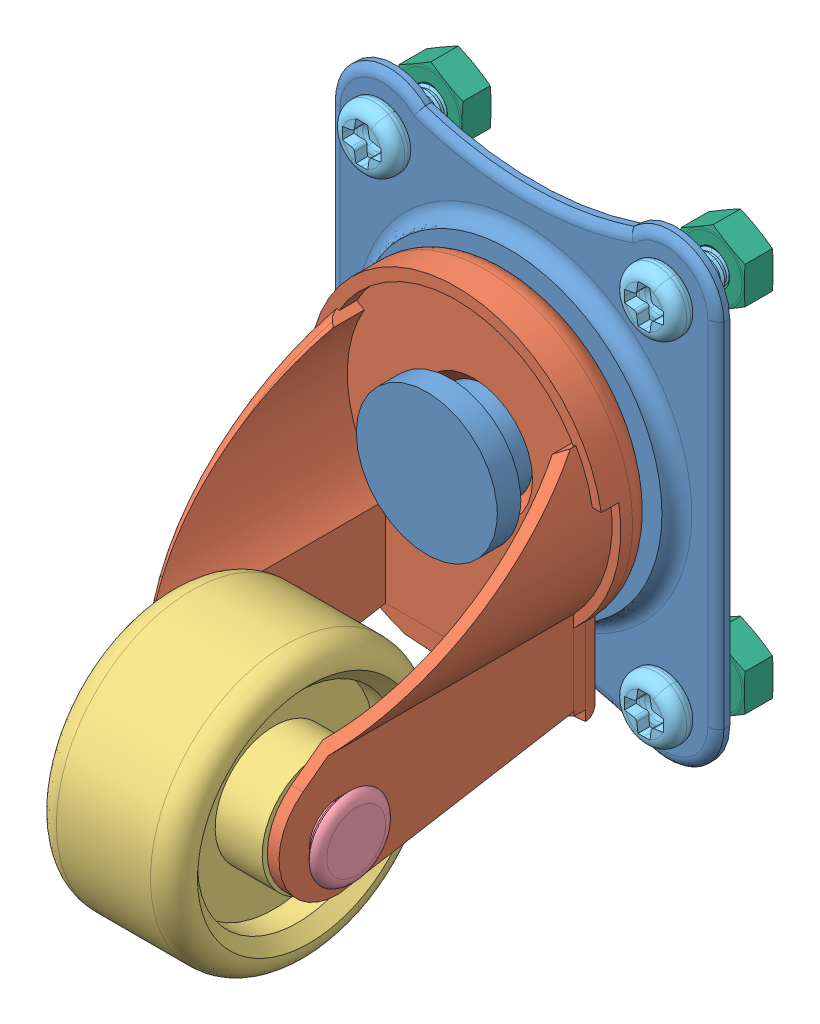
SolidWorks assembly CA, configuration Predeterminado. Lengths in mm.
Overall size (33 45.94 43.2).
13 component instances, 6 part files, 16 mates.
Components (placement in the parent):
- Caster Wheel-1: Caster Wheel [Default] at (57.6387 -78.841 57.7572) x (0 1 0) z (-1 0 0) size (45.94 37.59 33)
  - caster holder-1: caster holder [Default] at (-24.0751 44.7184 29.5137) x (1 0 0) z (0 0 -1) size (39 9.27 33)
  - holder-1: holder [Default] at (-1.5751 42.9484 46.0137) x (0 0 1) z (1 0 0) size (25 28.07 31.31)
  - caster wheel-1: caster wheel [Default] at (-15.6961 19.9484 46.0137) x (0.997275 0.073773 0) z (0 0 1) size (23 23 14)
  - Part4-1: Part4 [Default] at (-15.6961 19.9484 55.0137) x (-0.978448 0.206495 0) z (0 0 -1) size (7 7 20)
- M3x6 Philips Screw-1: M3x6 Philips Screw [Predeterminado] at (23.625 -65.4161 13.5389) size (5.3 5.3 7.81)
- M3x6 Philips Screw-2: M3x6 Philips Screw [Predeterminado] at (-0.375 -65.4161 13.5389) size (5.3 5.3 7.81)
- M3x6 Philips Screw-3: M3x6 Philips Screw [Predeterminado] at (-0.375 -95.4161 13.5389) size (5.3 5.3 7.81)
- M3x6 Philips Screw-4: M3x6 Philips Screw [Predeterminado] at (23.625 -95.4161 13.5389) size (5.3 5.3 7.81)
- M3 Nut-1: M3 Nut [Predeterminado] at (23.625 -65.4161 11.0389) size (6.27 6.27 2.71)
- M3 Nut-2: M3 Nut [Predeterminado] at (-0.375 -65.4161 11.0389) size (6.27 6.27 2.71)
- M3 Nut-3: M3 Nut [Predeterminado] at (-0.375 -95.4161 11.0389) size (6.27 6.27 2.71)
- M3 Nut-4: M3 Nut [Predeterminado] at (23.625 -95.4161 11.0389) size (6.27 6.27 2.71)
Mates (geometry in assembly coordinates):
- Concéntrica8: concentric: circle of Caster Wheel-1/caster holder-1; circle of M3x6 Philips Screw-1
- Coincidente5: coincident: plane of Caster Wheel-1/caster holder-1 through (11.625 -35.6179 13.5389) normal (0 0 1); plane of M3x6 Philips Screw-1 through (23.625 -63.8161 13.5389) normal (0 0 -1)
- Concéntrica9: concentric: circle of Caster Wheel-1/caster holder-1; cylinder of M3x6 Philips Screw-4 through (23.625 -95.4161 11.4389) axis (0 0 -1) radius 2.65
- Coincidente6: coincident: plane of Caster Wheel-1/caster holder-1 through (11.625 -35.6179 13.5389) normal (0 0 1); plane of M3x6 Philips Screw-4 through (23.625 -93.8161 13.5389) normal (0 0 -1)
- Concéntrica10: concentric: circle of Caster Wheel-1/caster holder-1; circle of M3x6 Philips Screw-2
- Coincidente7: coincident: plane of Caster Wheel-1/caster holder-1 through (11.625 -35.6179 13.5389) normal (0 0 1); plane of M3x6 Philips Screw-2 through (-0.375 -63.8161 13.5389) normal (0 0 -1)
- Concéntrica11: concentric: circle of Caster Wheel-1/caster holder-1; circle of M3x6 Philips Screw-3
- Coincidente8: coincident: plane of Caster Wheel-1/caster holder-1 through (11.625 -35.6179 13.5389) normal (0 0 1); plane of M3x6 Philips Screw-3 through (-0.375 -93.8161 13.5389) normal (0 0 -1)
- Distancia1: distance = 3 mm: plane of M3 Nut-1 through (23.625 -65.4161 9.5389) normal (0 0 1); plane of Caster Wheel-1/caster holder-1 through (11.625 -35.6179 12.5389) normal (0 0 -1)
- Concéntrica12: concentric: circle of Caster Wheel-1/caster holder-1; circle of M3 Nut-1
- Distancia2: distance = 3 mm: plane of M3 Nut-2 through (-0.375 -65.4161 9.5389) normal (0 0 1); plane of Caster Wheel-1/caster holder-1 through (11.625 -35.6179 12.5389) normal (0 0 -1)
- Concéntrica13: concentric: circle of Caster Wheel-1/caster holder-1; circle of M3 Nut-2
- Distancia3: distance = 3 mm: plane of M3 Nut-3 through (-0.375 -95.4161 9.5389) normal (0 0 1); plane of Caster Wheel-1/caster holder-1 through (11.625 -35.6179 12.5389) normal (0 0 -1)
- Concéntrica14: concentric: circle of Caster Wheel-1/caster holder-1; circle of M3 Nut-3
- Distancia4: distance = 3 mm: plane of M3 Nut-4 through (23.625 -95.4161 9.5389) normal (0 0 1); plane of Caster Wheel-1/caster holder-1 through (11.625 -35.6179 12.5389) normal (0 0 -1)
- Concéntrica15: concentric: circle of Caster Wheel-1/caster holder-1; circle of M3 Nut-4
